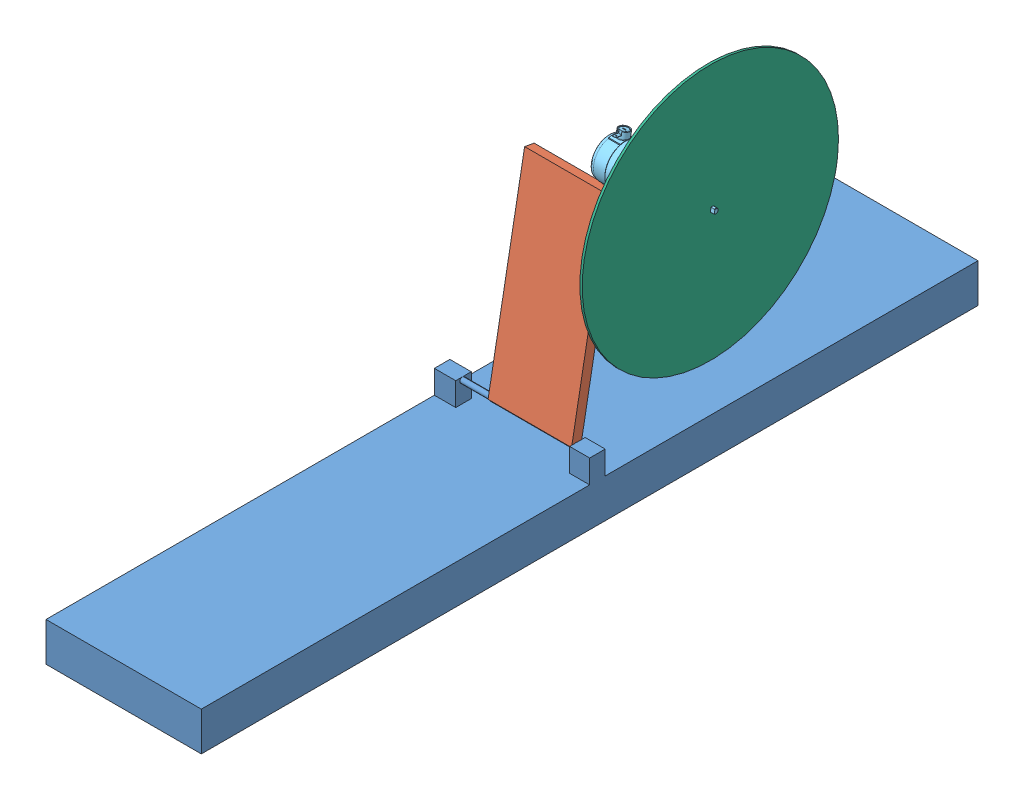
SolidWorks assembly Assemblage1, configuration Défaut. Lengths in mm.
Overall size (296.81 555.84 1000).
7 component instances, 6 part files, 9 mates.
Components (placement in the parent):
- bati-1: bati [Défaut] at (239.2165 82.5437 956.291) size (200 80 1000)
- Pièce1-1: Pièce1 [Défaut] at (205.952 276.7508 474.165) x (1 0 0) z (0 0.179224 0.983808) size (107.5 266.5 12.5)
- rs51_t-1: rs51_t [Default] at (366.2968 437.8356 346.7724) x (0.990406 -0.137992 0.007378) z (-0.005308 0.015366 0.999868) size (132.43 72.97 87.19)
  - rs51_t_01-1: rs51_t_01 [Default] at origin size (4.2 4.2 2.46)
  - rs51_t_02-1: rs51_t_02 [Default] at origin size (4.2 4.2 2.46)
  - rs51_t_03-1: rs51_t_03 [Default] at origin size (132.43 72.97 54.23)
- Pièce2-1: Pièce2 [Défaut] at (424.282 435.0837 439.0092) x (1 0 0) z (0 0.179224 0.983808) size (3 330 330)
Mates (geometry in assembly coordinates):
- Coaxiale2: concentric aligned: cylinder of bati-1 through (151.7657 147.6956 497.6755) axis (1 0 0) radius 3.4481; cylinder of Pièce1-1 through (204.952 147.6956 497.6755) axis (1 0 0) radius 3.8
- Coïncidente1: coincident anti-aligned: plane of bati-1 through (313.452 151.1437 956.291) normal (-1 0 0); plane of Pièce1-1 through (313.452 276.7508 474.165) normal (1 0 0)
- Coïncidente14: coincident anti-aligned: plane of rs51_t-1/rs51_t_03-1 through (432.152 440.6139 438.0017) normal (0 0.179224 0.983808); plane of Pièce2-1 through (414.282 435.0837 439.0092) normal (0 -0.179224 -0.983808)
- Parallèle1: parallel aligned: plane of rs51_t-1/rs51_t_03-1 through (432.152 440.6139 438.0017) normal (0 0.179224 0.983808); plane of Pièce2-1 through (414.282 434.1876 434.0901) normal (0 0.179224 0.983808)
- Tangent1: tangent anti-aligned: cylinder of rs51_t-1/rs51_t_03-1 through (414.662 437.8421 436.4636) axis (1 0 0) radius 3.17; plane of Pièce2-1 through (414.282 435.0837 439.0092) normal (0 0.983808 -0.179224)
- Coïncidente21: coincident anti-aligned: plane of rs51_t-1/rs51_t_03-1 through (424.282 438.2655 438.7875) normal (1 0 0); plane of Pièce2-1 through (424.282 435.0837 439.0092) normal (-1 0 0)
- Coïncidente25: coincident: point of Pièce1-1; point of rs51_t-1/rs51_t_03-1
- Coïncidente27: coincident anti-aligned: plane of Pièce1-1 through (313.452 406.9958 456.7907) normal (0 0.983808 -0.179224); circle of rs51_t-1/rs51_t_03-1
- Parallèle7: parallel anti-aligned: line of Pièce1-1 through (313.452 404.7555 444.4931) axis (-1 0 0); axis of rs51_t-1/rs51_t_03-1 through (414.662 437.8421 436.4636) axis (1 0 0)
